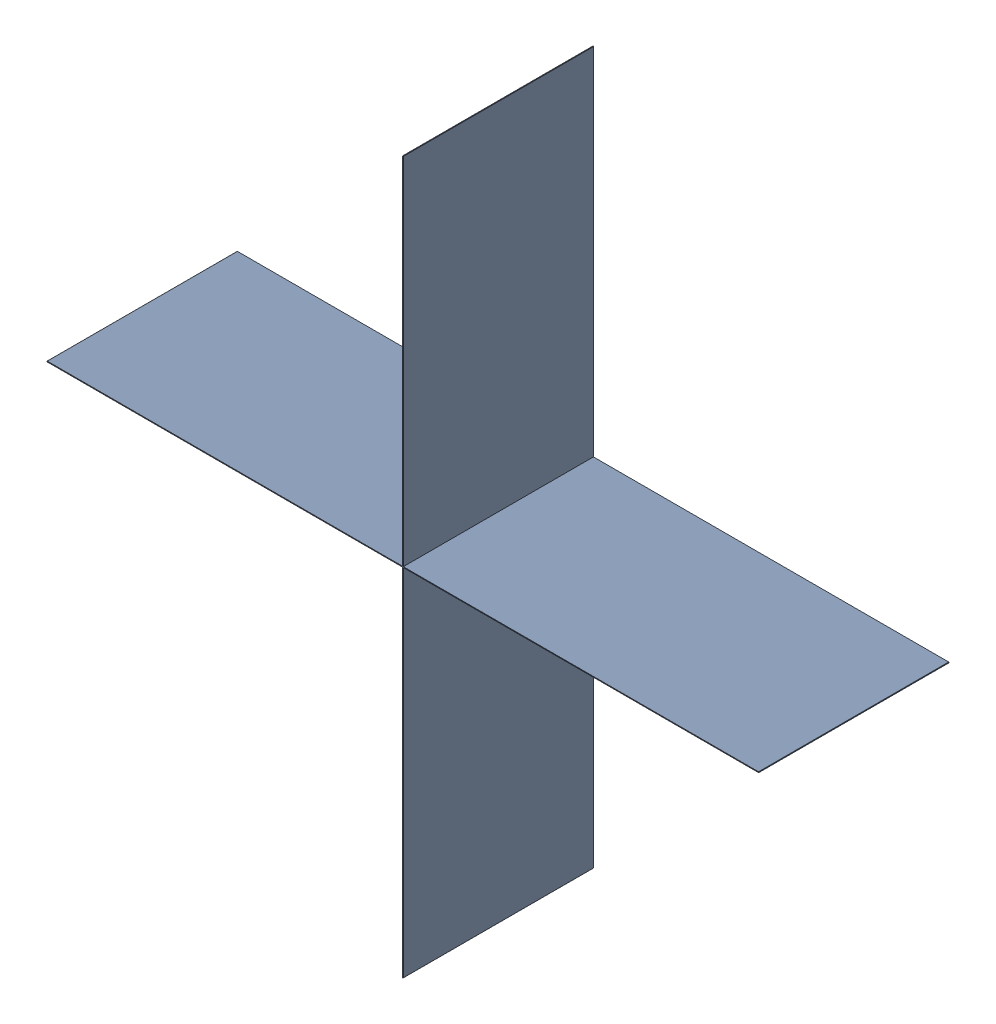
SolidWorks assembly 6327400960, configuration Default. Lengths in mm.
Overall size (0.95 0.95 0.25).
2 component instances, 1 part files, 0 mates.
Components (placement in the parent):
- 6701982208-1:  [Default] at (27.7 14.8 0) (suppressed, hidden)
- Extruded-14-1: Extruded-14 [Default] at origin size (0.95 0.95 0.25)
